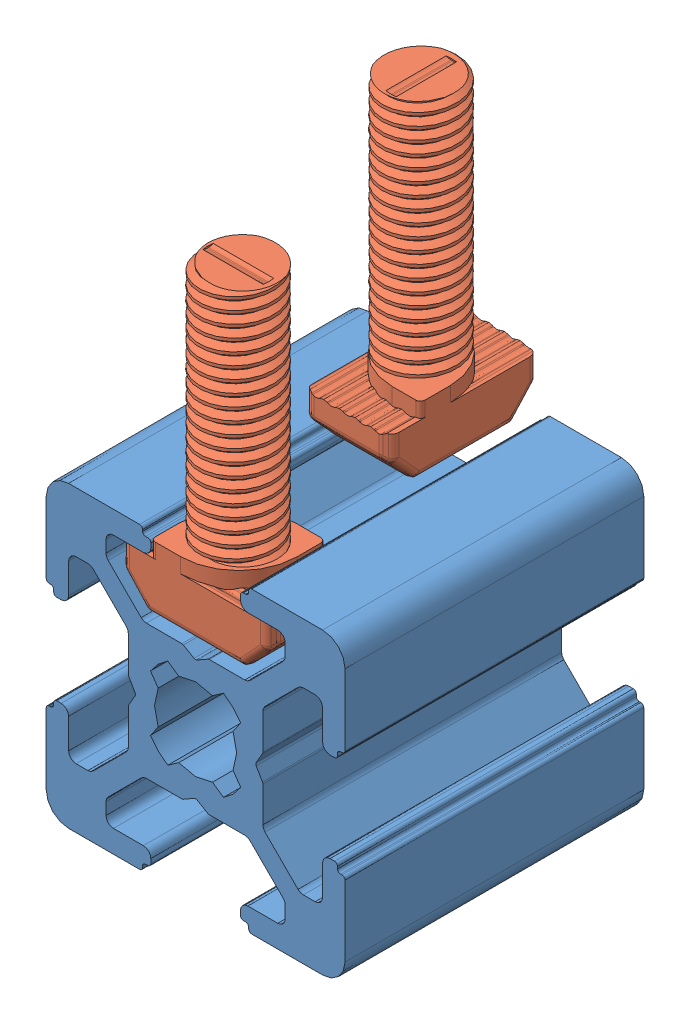
SolidWorks assembly Сборка Т-Болт 6 паз M5, configuration По умолчанию. Lengths in mm.
Overall size (20 40.75 20).
3 component instances, 2 part files, 9 mates.
Components (placement in the parent):
- 20х20 для сборки болта 6 паз-1: 20х20 для сборки болта 6 паз [По умолчанию] at origin size (20 20 20)
- Т-Болт 6 паз M5x16-1: Т-Болт 6 паз M5x16 [По умолчанию] at (-0.05 5.1 17.1) size (10 20.75 5.8)
- Т-Болт 6 паз M5x16-2: Т-Болт 6 паз M5x16 [По умолчанию] at (0.1 10 5) x (0 0 -1) z (1 0 0) size (10 20.75 5.8)
Mates (geometry in assembly coordinates):
- Совпадение2: coincident: point of 20х20 для сборки болта 6 паз-1
- Параллельность2: parallel anti-aligned: plane of 20х20 для сборки болта 6 паз-1 through (0 -10 20) normal (0 -1 0)
- Параллельность3: parallel anti-aligned: plane of 20х20 для сборки болта 6 паз-1 through (-10 0 20) normal (-1 0 0)
- Совпадение8: coincident: plane of 20х20 для сборки болта 6 паз-1 through (0 8.5 20) normal (0 -1 0); line of Т-Болт 6 паз M5x16-1 through (1.878 8.5 18.732) axis (1 0 0)
- Совпадение9: coincident aligned: plane of 20х20 для сборки болта 6 паз-1 through (0 0 20) normal (0 0 1); plane of Т-Болт 6 паз M5x16-1 through (-0.05 5.1 20) normal (0 0 1)
- Совпадение10: coincident anti-aligned: plane of 20х20 для сборки болта 6 паз-1 through (-3 0 20) normal (1 0 0); plane of Т-Болт 6 паз M5x16-1 through (-3 8.5 14.2) normal (-1 0 0)
- Совпадение11: coincident anti-aligned: plane of 20х20 для сборки болта 6 паз-1 through (3 0 20) normal (-1 0 0); plane of Т-Болт 6 паз M5x16-2 through (3 10 5) normal (1 0 0)
- Совпадение12: coincident aligned: plane of 20х20 для сборки болта 6 паз-1 through (0 0 0) normal (0 0 -1); plane of Т-Болт 6 паз M5x16-2 through (-2.8 11.9 0) normal (0 0 -1)
- Совпадение13: coincident anti-aligned: plane of 20х20 для сборки болта 6 паз-1 through (0 10 20) normal (0 1 0); plane of Т-Болт 6 паз M5x16-2 through (-2.8 10 1.75) normal (0 -1 0)
